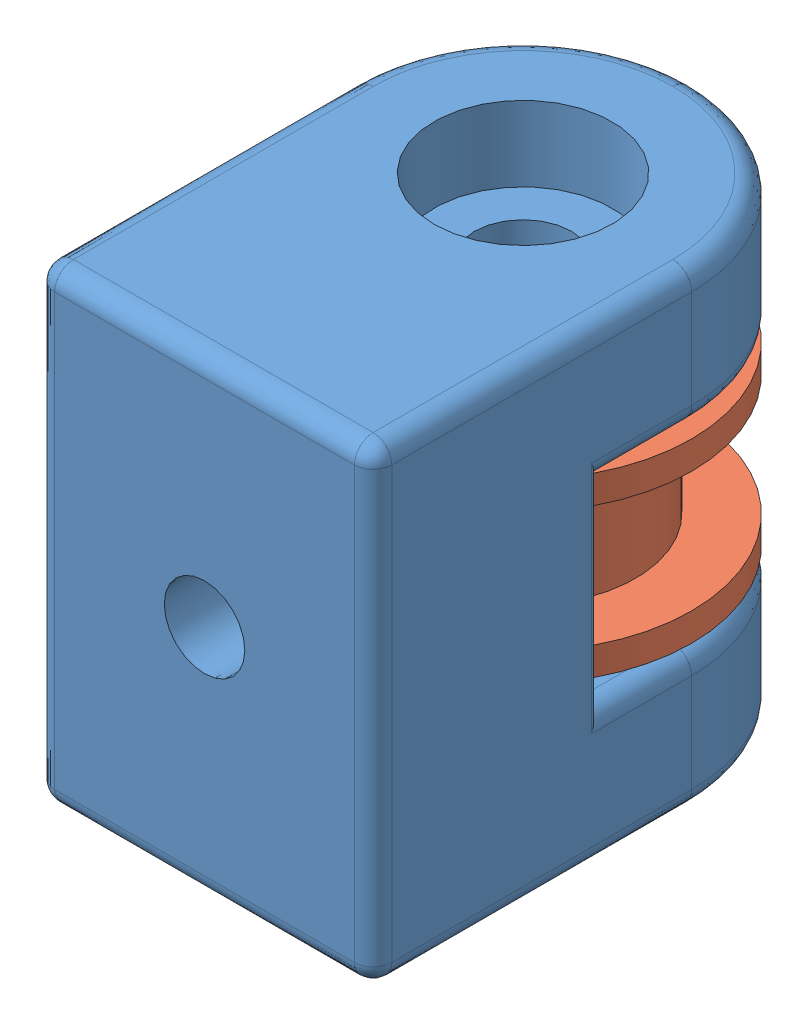
SolidWorks assembly Assem10, configuration Default. Lengths in mm.
Overall size (18 25 26).
5 component instances, 3 part files, 2 mates.
Components (placement in the parent):
- PulleyTensioner-1: PulleyTensioner [Default] at (-6.4589 8.348 18.8423) size (18 25 26)
- 1037396-1: 1037396 [Default] at (2.5411 8.323 5.8423) size (18 9.45 18)
  - 1037396-IDLER PULLEY-1: 1037396-IDLER PULLEY [Default] at origin size (18 9.45 18)
  - 1037396-95-2Z BEARING, 9 mm OD, 5 mm ID, 3 mm WIDTH-1: 1037396-95-2Z BEARING, 9 mm OD, 5 mm ID, 3 mm WIDTH [DEFAULT] at (0 3.225 0) x (0.884042 0 0.467408) z (0 1 0) size (9 9 3)
  - 1037396-95-2Z BEARING, 9 mm OD, 5 mm ID, 3 mm WIDTH-2: 1037396-95-2Z BEARING, 9 mm OD, 5 mm ID, 3 mm WIDTH [DEFAULT] at (0 -3.225 0) x (-0.884042 0 -0.467408) z (0 -1 0) size (9 9 3)
Mates (geometry in assembly coordinates):
- Concentric1: concentric aligned: cylinder of PulleyTensioner-1 through (2.5411 -4.152 5.8423) axis (0 1 0) radius 2.6; cylinder of 1037396-1/1037396-95-2Z BEARING, 9 mm OD, 5 mm ID, 3 mm WIDTH-1 through (2.5411 13.048 5.8423) axis (0 1 0) radius 2.5
- Distance1: distance = 0.5 mm anti-aligned: plane of 1037396-1/1037396-IDLER PULLEY-1 through (2.5411 3.598 5.8423) normal (0 -1 0); plane of PulleyTensioner-1 through (11.5411 3.098 18.8423) normal (0 1 0)
